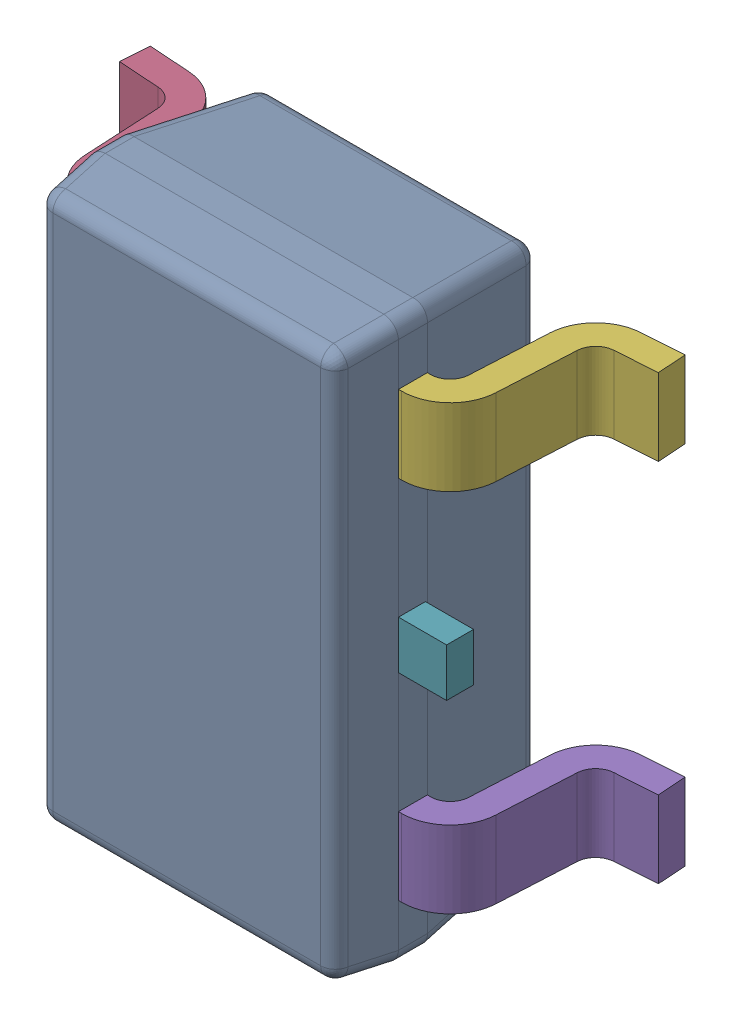
SolidWorks assembly 6348794768_1.step, configuration Default. Lengths in mm.
Overall size (2.8 2.9 1.2).
7 component instances, 3 part files, 0 mates.
Components (placement in the parent):
- BODY-SOT-9_1.step-11: BODY-SOT-9_1.step [Default] at (0 0 0.9) x (0 -1 0) z (-1 0 0) size (2.9 1.1 1.6)
- LEAD-SOT-10_1.step-53: LEAD-SOT-10_1.step [Default] at (-0.9395 -0.95 0.25) x (0 -1 0) z (-1 0 0) size (0.4 0.9 0.6)
- LEAD-SOT-10_1.step-54: LEAD-SOT-10_1.step [Default] at (-0.9395 0 0.25) x (0 -1 0) z (-1 0 0) size (0.4 0.9 0.6)
- LEAD-SOT-10_1.step-55: LEAD-SOT-10_1.step [Default] at (-0.9395 0.95 0.25) x (0 -1 0) z (-1 0 0) size (0.4 0.9 0.6)
- LEAD-SOT-10_1.step-56: LEAD-SOT-10_1.step [Default] at (0.9395 -0.95 0.25) x (0 1 0) z (1 0 0) size (0.4 0.9 0.6)
- LEAD-SOT-10_1.step-57: LEAD-SOT-10_1.step [Default] at (0.9395 0.95 0.25) x (0 1 0) z (1 0 0) size (0.4 0.9 0.6)
- LEAD-DUMMY-11_1.step-11: LEAD-DUMMY-11_1.step [Default] at (1.05 0 0.76) x (0 -1 0) z (-1 0 0) size (0.25 0.14 0.25)
